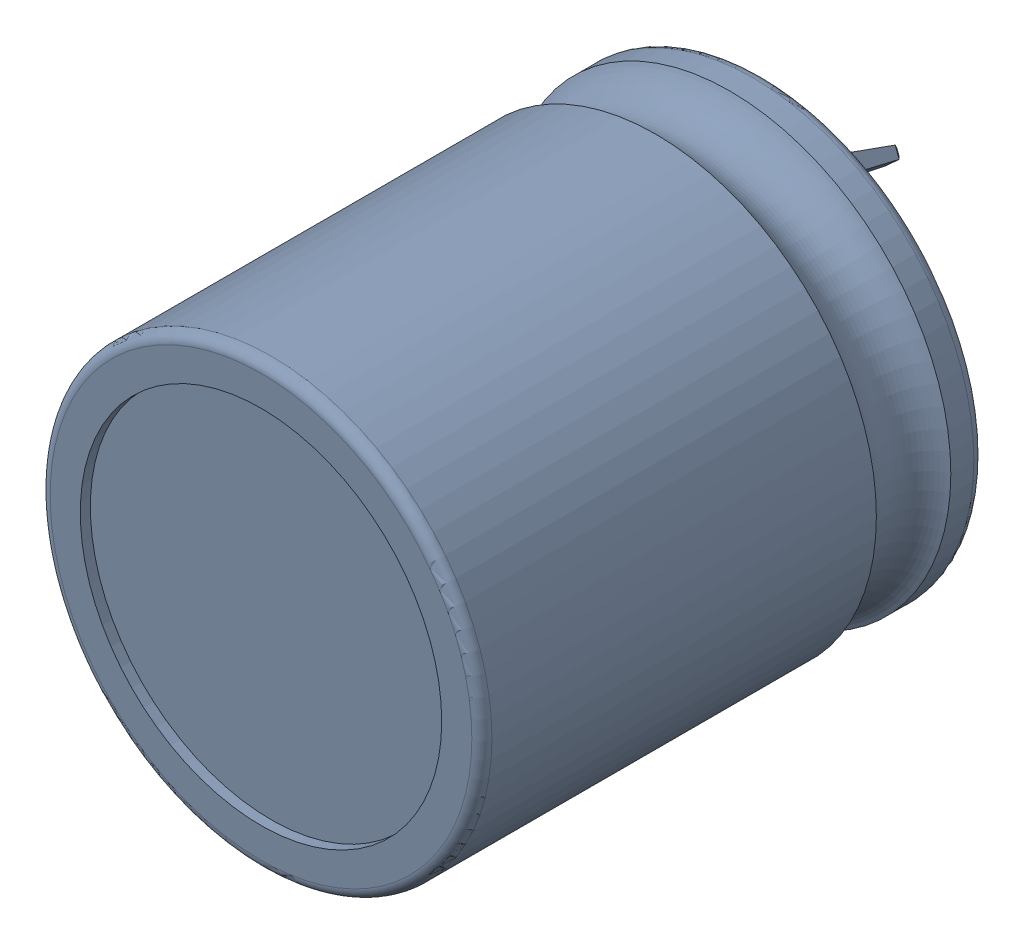
SolidWorks assembly C4, configuration Default. Lengths in mm.
Overall size (22 22 31.01).
4 component instances, 2 part files, 0 mates.
Components (placement in the parent):
- Capacitor22x25-1: Capacitor22x25 [Default] at (120.4421 20.3032 -3.686) x (0 -1 0) z (-1 0 0) size (22 31.01 22)
  - User_Library-ECEC2DP271BJ-1: User_Library-ECEC2DP271BJ [Default] at (8.9531 3.6858 17.317) size (22 25.01 22)
  - User_Library-CAP_EL_SNAP-IN_10_35x45_Valor_predeterminado-1: User_Library-CAP_EL_SNAP-IN_10_35x45_Valor_predeterminado [Default] at (14.4607 11.8368 29.4898) x (0.642788 0 0.766044) z (-0.766044 0 0.642788) size (3.5 7.01 5.68)
  - User_Library-CAP_EL_SNAP-IN_10_35x45_Valor_predeterminado-2: User_Library-CAP_EL_SNAP-IN_10_35x45_Valor_predeterminado [Default] at (2.8917 11.8368 4.8301) x (-0.67559 0 -0.737277) z (0.737277 0 -0.67559) size (3.5 7.01 5.68)
